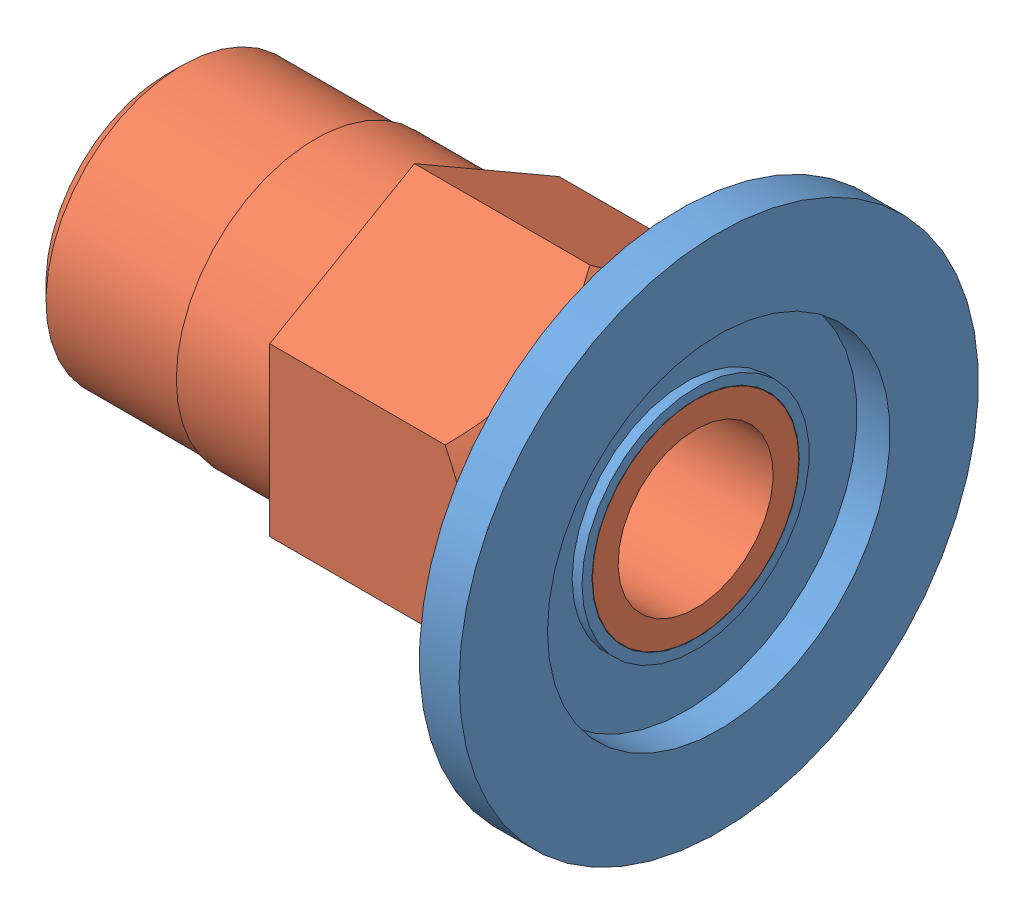
SolidWorks assembly 731024, configuration Default. Lengths in mm.
Overall size (42.42 39.88 39.88).
2 component instances, 2 part files, 3 mates.
Components (placement in the parent):
- 961043-1: 961043 [Default] at (4.9901 20.7231 34.5505) size (5.08 39.88 39.88)
- 731024-1: 731024 [Default] at (8.2921 20.7231 34.5505) x (0 0.866025 -0.5) z (-1 0 0) size (22.23 28.23 40.64)
Mates (geometry in assembly coordinates):
- Coincident1: coincident aligned: plane of 961043-1 through (8.2921 29.448 34.5505) normal (1 0 0); plane of 731024-1 through (19.9386 -4.0902 34.5505) normal (1 0 0)
- Concentric1: concentric anti-aligned: cylinder of 961043-1 through (4.9901 20.7231 34.5505) axis (-1 0 0) radius 7.9629; cylinder of 731024-1 through (15.1126 -4.0902 34.5505) axis (1 0 0) radius 7.9248
- Parallel1: parallel anti-aligned: plane of 731024-1 through (-13.2979 27.1389 23.438) normal (0 0 -1)
